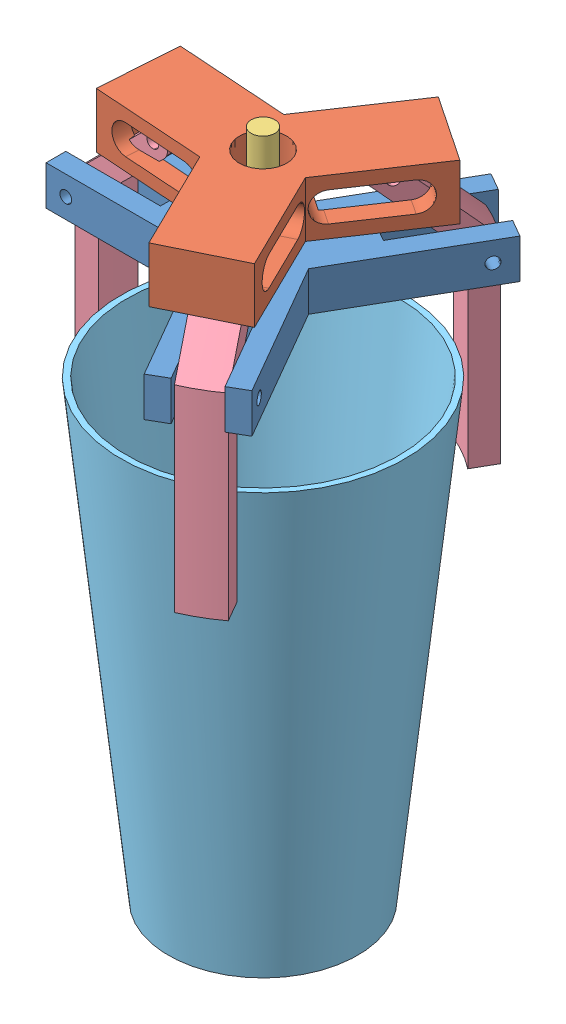
SolidWorks assembly Grabber2020, configuration Default. Lengths in mm.
Overall size (93.26 169.98 93.26).
5 component instances, 5 part files, 4 mates.
Components (placement in the parent):
- Grabber2020-BottomCross-1: Grabber2020-BottomCross [Default] at (15.4973 17.7015 42.3541) size (76.16 10 87.94)
- Grabber2020-TopCross-1: Grabber2020-TopCross [Default] at (15.4973 34.0673 42.3541) x (0.997717 0 0.067541) z (-0.067541 0 0.997717) size (59.66 14 68.89)
- Grabber2020-Link-1: Grabber2020-Link [Default] at (15.4973 13.1385 42.3541) x (-0.43877 0 -0.898599) z (0 1 0) size (6 6 40)
- Grabber2020-Part-1: Grabber2020-Part [Default] at (15.4973 23.4589 42.3541) size (68.68 70.14 78.97)
- Eurobot2020_Glass-1: Eurobot2020_Glass [Default] at (15.4973 -1.8398 42.3541) x (0.931499 0 -0.363744) z (-0.363744 0 -0.931499) size (72 115 72)
Mates (geometry in assembly coordinates):
- Concentric1: concentric anti-aligned: cylinder of Grabber2020-BottomCross-1 through (15.4973 17.7015 42.3541) axis (0 1 0) radius 3; cylinder of Grabber2020-Link-1 through (15.4973 53.1385 42.3541) axis (0 -1 0) radius 3
- Coincident3: coincident aligned: circle of Grabber2020-BottomCross-1; cylinder of Grabber2020-Part-1 through (-24.5027 22.7015 20.8541) axis (0 0 1) radius 1.5
- Concentric11: concentric aligned: circle of Grabber2020-TopCross-1; circle of Grabber2020-Link-1
- Concentric12: concentric anti-aligned: circle of Grabber2020-TopCross-1; circle of Eurobot2020_Glass-1
